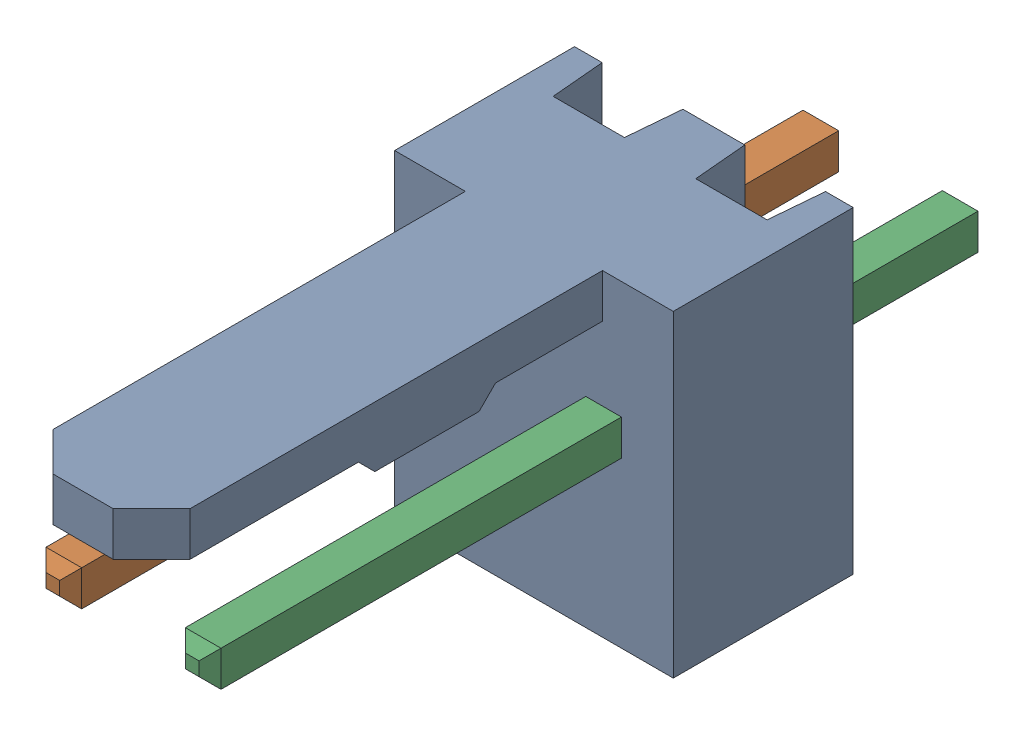
SolidWorks assembly Molex PCB 2 pin v2_1, configuration Default. Lengths in mm.
Overall size (5.08 5.79 14.92).
3 component instances, 2 part files, 0 mates.
Components (placement in the parent):
- BASE9710016_1-1: BASE9710016_1 [Default] at (2.54 2.895 -8.22) size (5.08 5.79 11.5)
- PINO9710016_1-1: PINO9710016_1 [Default] at (1.27 3.325 -0.72) size (0.65 0.65 14.2)
- PINO9710016_1-2: PINO9710016_1 [Default] at (3.81 3.325 -0.72) size (0.65 0.65 14.2)
